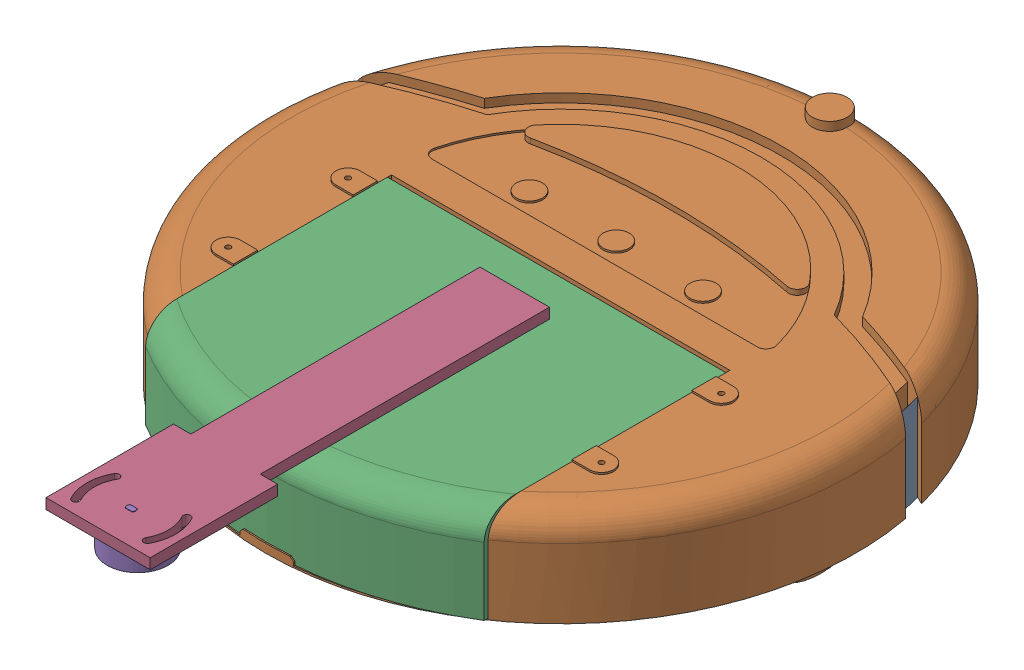
SolidWorks assembly SECOND, configuration Default. Lengths in mm.
Overall size (340 81.2 436.46).
5 component instances, 4 part files, 7 mates.
Components (placement in the parent):
- SMART_Redesign_Assembly-1: SMART_Redesign_Assembly [Default] at (126.3973 128.0959 105.5245) size (340 80 340)
  - roomba of doom - Copy-1: roomba of doom - Copy [Default] at origin size (340 80 340)
  - attachments-1: attachments [Default] at (0 1 -16.4606) size (195 60.9 166.92)
- SECONDARY PART-1: SECONDARY PART [Default] at (126.3973 183.0959 251.9895) size (60 14 240)
- Stepper Motor-1: Stepper Motor [Default] at (121.3973 162.5959 344.2036) x (-1 0 0) z (0 0 -1) size (43.37 26.7 37.5)
Mates (geometry in assembly coordinates):
- Coincident1: coincident anti-aligned: plane of SMART_Redesign_Assembly-1/attachments-1 through (112.3973 175.0959 141.9895) normal (0 0 1); plane of SECONDARY PART-1 through (112.3973 175.0959 141.9895) normal (0 0 -1)
- Coincident2: coincident anti-aligned: plane of SMART_Redesign_Assembly-1/attachments-1 through (142.3973 129.0959 89.0639) normal (-1 0 0); plane of SECONDARY PART-1 through (142.3973 183.0959 251.9895) normal (1 0 0)
- Coincident3: coincident anti-aligned: plane of SMART_Redesign_Assembly-1/attachments-1 through (126.3973 175.0959 89.0639) normal (0 1 0); plane of SECONDARY PART-1 through (126.3973 175.0959 251.9895) normal (0 -1 0)
- Parallel1: parallel anti-aligned: plane of SECONDARY PART-1 through (126.3973 183.0959 251.9895) normal (0 -1 0); plane of Stepper Motor-1 through (121.3973 179.5959 344.2036) normal (0 1 0)
- Coincident6: coincident anti-aligned: plane of SECONDARY PART-1 through (124.3473 193.0959 354.3638) normal (0 0 -1); plane of Stepper Motor-1 through (128.3973 189.2959 354.3638) normal (0 0 1)
- Concentric1: concentric aligned: cylinder of SECONDARY PART-1 through (126.3973 193.0959 352.8638) axis (0 -1 0) radius 2.5402; cylinder of Stepper Motor-1 through (126.3973 183.0959 352.8638) axis (0 -1 0) radius 2.5
- Coincident7: coincident anti-aligned: plane of SECONDARY PART-1 through (126.3973 183.0959 251.9895) normal (0 -1 0); plane of Stepper Motor-1 through (126.3973 183.0959 352.8638) normal (0 1 0)
